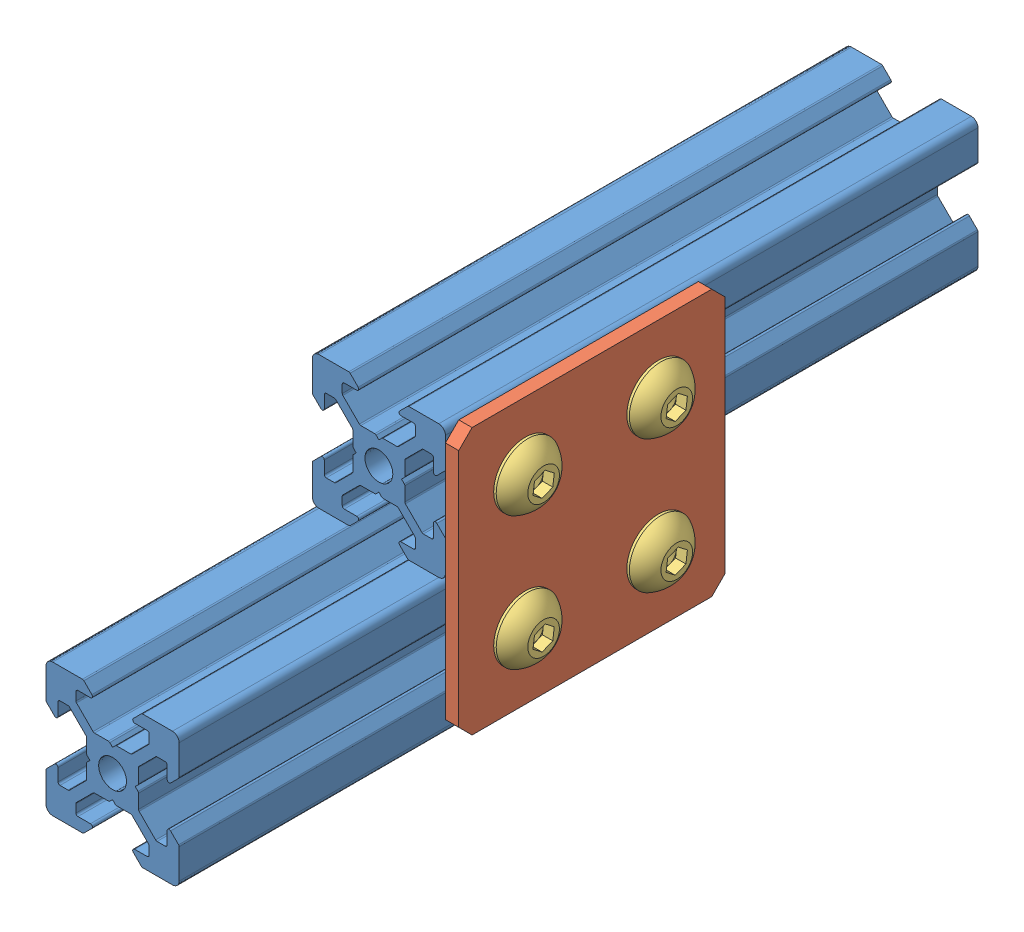
SolidWorks assembly П-Пластина 20 серия 2х2 4отв 40х40х2 СБ, configuration По умолчанию. Lengths in mm.
Overall size (24.75 40 120).
7 component instances, 3 part files, 14 mates.
Components (placement in the parent):
- 2020100-1: 2020100 [По умолчанию] at origin size (20 20 80)
- 2020100-2: 2020100 [По умолчанию] at (0 20 -40) size (20 20 80)
- П-Пластина 20 серия 2х2 4отв 40х40х2-1: П-Пластина 20 серия 2х2 4отв 40х40х2 [По умолчанию] at (10 10 20) x (0 0 -1) z (1 0 0) size (40 40 2)
- socket button head screw_iso-1: socket button head screw_iso [ISO 7380 - M5 x 10 - 10N] at (14.75 20 30) x (-1 0 0) z (0 0.924225 0.381849) size (12.75 9.5 9.5)
- socket button head screw_iso-2: socket button head screw_iso [ISO 7380 - M5 x 10 - 10N] at (14.75 20 10) x (-1 0 0) z (0 0.924225 0.381849) size (12.75 9.5 9.5)
- socket button head screw_iso-3: socket button head screw_iso [ISO 7380 - M5 x 10 - 10N] at (14.75 0 30) x (-1 0 0) z (0 0.924225 0.381849) size (12.75 9.5 9.5)
- socket button head screw_iso-4: socket button head screw_iso [ISO 7380 - M5 x 10 - 10N] at (14.75 0 10) x (-1 0 0) z (0 0.924225 0.381849) size (12.75 9.5 9.5)
Mates (geometry in assembly coordinates):
- Совпадение1: coincident aligned: plane of 2020100-1 through (10 10 80) normal (1 0 0); plane of 2020100-2 through (10 10 40) normal (1 0 0)
- Совпадение2: coincident anti-aligned: plane of 2020100-1 through (10 10 80) normal (0 1 0); plane of 2020100-2 through (10 10 40) normal (0 -1 0)
- Расстояние1: distance = 40 mm anti-aligned: plane of 2020100-1 through (0 0 0) normal (0 0 -1); plane of 2020100-2 through (0 20 40) normal (0 0 1)
- Совпадение4: coincident anti-aligned: plane of 2020100-1 through (10 10 80) normal (1 0 0); plane of П-Пластина 20 серия 2х2 4отв 40х40х2-1 through (10 10 20) normal (-1 0 0)
- Совпадение5: coincident aligned: plane of 2020100-1 through (10 -10 80) normal (0 -1 0); plane of П-Пластина 20 серия 2х2 4отв 40х40х2-1 through (12 -10 40) normal (0 -1 0)
- Совпадение6: coincident aligned: plane of 2020100-1 through (0 0 0) normal (0 0 -1); plane of П-Пластина 20 серия 2х2 4отв 40х40х2-1 through (12 -10 0) normal (0 0 -1)
- Концентричный1: concentric aligned: cylinder of П-Пластина 20 серия 2х2 4отв 40х40х2-1 through (12 20 30) axis (1 0 0) radius 2.75; cylinder of socket button head screw_iso-1 through (14.75 20 30) axis (1 0 0) radius 4.75
- Совпадение8: coincident anti-aligned: plane of П-Пластина 20 серия 2х2 4отв 40х40х2-1 through (12 10 20) normal (1 0 0); plane of socket button head screw_iso-1 through (12 19.0454 32.3106) normal (-1 0 0)
- Концентричный2: concentric aligned: cylinder of П-Пластина 20 серия 2х2 4отв 40х40х2-1 through (12 20 10) axis (1 0 0) radius 2.75; cylinder of socket button head screw_iso-2 through (14.75 20 10) axis (1 0 0) radius 4.75
- Совпадение9: coincident anti-aligned: plane of П-Пластина 20 серия 2х2 4отв 40х40х2-1 through (12 10 20) normal (1 0 0); plane of socket button head screw_iso-2 through (12 19.0454 12.3106) normal (-1 0 0)
- Концентричный3: concentric aligned: cylinder of П-Пластина 20 серия 2х2 4отв 40х40х2-1 through (12 0 30) axis (1 0 0) radius 2.75; cylinder of socket button head screw_iso-3 through (14.75 0 30) axis (1 0 0) radius 4.75
- Совпадение10: coincident anti-aligned: plane of П-Пластина 20 серия 2х2 4отв 40х40х2-1 through (12 10 20) normal (1 0 0); plane of socket button head screw_iso-3 through (12 -0.9546 32.3106) normal (-1 0 0)
- Концентричный4: concentric aligned: cylinder of П-Пластина 20 серия 2х2 4отв 40х40х2-1 through (12 0 10) axis (1 0 0) radius 2.75; cylinder of socket button head screw_iso-4 through (14.75 0 10) axis (1 0 0) radius 4.75
- Совпадение11: coincident anti-aligned: plane of П-Пластина 20 серия 2х2 4отв 40х40х2-1 through (12 10 20) normal (1 0 0); plane of socket button head screw_iso-4 through (12 -0.9546 12.3106) normal (-1 0 0)
